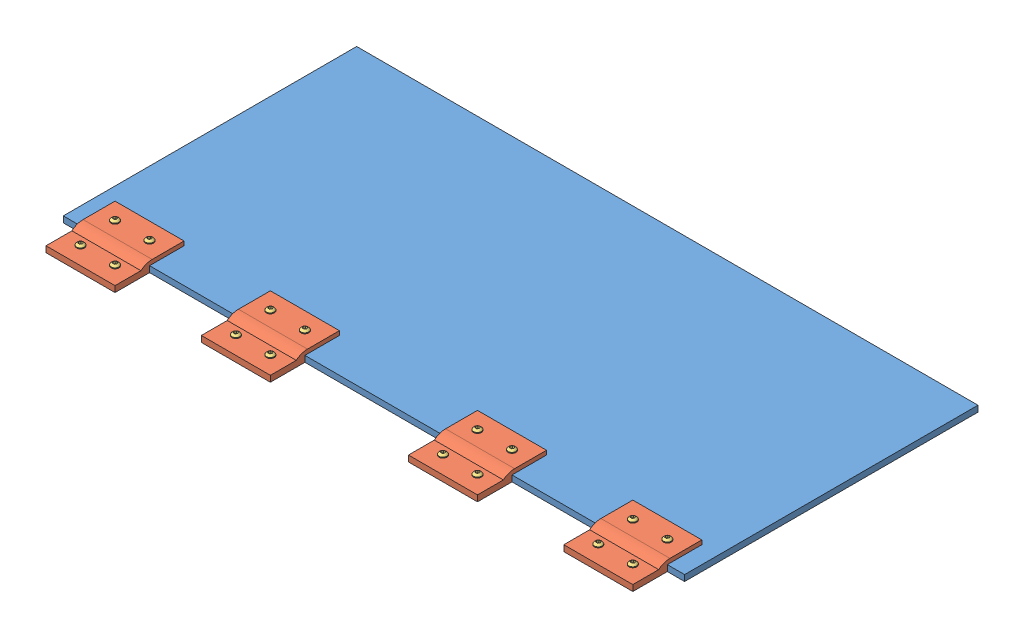
SolidWorks assembly Enclosure_left_side, configuration Default. Lengths in mm.
Overall size (360 12.64 195).
37 component instances, 5 part files, 0 mates.
Components (placement in the parent):
- Left_plexiglass_panel-1: Left_plexiglass_panel [Default] at (-180 0 0) size (360 3.5 170)
- Enclosure_holder-1: Enclosure_holder [Default] at (-170 0 20) size (40 5.5 25)
- M3x8-1: M3x8 [Default] at (-160 5.9 -10) size (4.5 9.55 4.5)
- M3x8-2: M3x8 [Default] at (-140 5.9 -10) size (4.5 9.55 4.5)
- M3x8-3: M3x8 [Default] at (-140 3.5 10) size (4.5 9.55 4.5)
- M3x8-4: M3x8 [Default] at (-160 3.5 10) size (4.5 9.55 4.5)
- M3_nut-1: M3_nut [Default] at (-160 0 -10) x (1 0 0) z (0 0 -1) size (5.5 2.58 6.35)
- M3_nut-2: M3_nut [Default] at (-140 0 -10) x (1 0 0) z (0 0 -1) size (5.5 2.58 6.35)
- M3_t_nut-1: M3_t_nut [Default] at (-160 -5 10) x (0 0 -1) z (1 0 0) size (10 5.19 6)
- M3_t_nut-3: M3_t_nut [Default] at (-140 -5 10) x (0 0 -1) z (1 0 0) size (10 5.19 6)
- M3_t_nut-4: M3_t_nut [Default] at (-50 -5 10) x (0 0 -1) z (1 0 0) size (10 5.19 6)
- M3_t_nut-5: M3_t_nut [Default] at (-70 -5 10) x (0 0 -1) z (1 0 0) size (10 5.19 6)
- M3_nut-3: M3_nut [Default] at (-50 0 -10) x (1 0 0) z (0 0 -1) size (5.5 2.58 6.35)
- M3_nut-4: M3_nut [Default] at (-70 0 -10) x (1 0 0) z (0 0 -1) size (5.5 2.58 6.35)
- M3x8-5: M3x8 [Default] at (-70 3.5 10) size (4.5 9.55 4.5)
- M3x8-6: M3x8 [Default] at (-50 3.5 10) size (4.5 9.55 4.5)
- M3x8-7: M3x8 [Default] at (-50 5.9 -10) size (4.5 9.55 4.5)
- M3x8-8: M3x8 [Default] at (-70 5.9 -10) size (4.5 9.55 4.5)
- Enclosure_holder-2: Enclosure_holder [Default] at (-80 0 20) size (40 5.5 25)
- Enclosure_holder-3: Enclosure_holder [Default] at (40 0 20) size (40 5.5 25)
- M3x8-9: M3x8 [Default] at (50 5.9 -10) x (-1 0 0) z (0 0 -1) size (4.5 9.55 4.5)
- M3_t_nut-6: M3_t_nut [Default] at (50 -0.1867 10) x (0 0 -1) z (-1 0 0) size (10 5.19 6)
- M3_nut-5: M3_nut [Default] at (50 0 -10) x (-1 0 0) z (0 0 1) size (5.5 2.58 6.35)
- M3x8-10: M3x8 [Default] at (70 3.5 10) x (-1 0 0) z (0 0 -1) size (4.5 9.55 4.5)
- M3x8-11: M3x8 [Default] at (50 3.5 10) x (-1 0 0) z (0 0 -1) size (4.5 9.55 4.5)
- M3_nut-6: M3_nut [Default] at (70 0 -10) x (-1 0 0) z (0 0 1) size (5.5 2.58 6.35)
- M3x8-12: M3x8 [Default] at (70 5.9 -10) x (-1 0 0) z (0 0 -1) size (4.5 9.55 4.5)
- M3_t_nut-7: M3_t_nut [Default] at (70 -0.1867 10) x (0 0 -1) z (-1 0 0) size (10 5.19 6)
- M3_nut-7: M3_nut [Default] at (160 0 -10) x (-1 0 0) z (0 0 1) size (5.5 2.58 6.35)
- M3_nut-8: M3_nut [Default] at (140 0 -10) x (-1 0 0) z (0 0 1) size (5.5 2.58 6.35)
- M3_t_nut-8: M3_t_nut [Default] at (140 -0.1867 10) x (0 0 -1) z (-1 0 0) size (10 5.19 6)
- M3x8-13: M3x8 [Default] at (140 5.9 -10) x (-1 0 0) z (0 0 -1) size (4.5 9.55 4.5)
- M3x8-14: M3x8 [Default] at (160 3.5 10) x (-1 0 0) z (0 0 -1) size (4.5 9.55 4.5)
- Enclosure_holder-4: Enclosure_holder [Default] at (130 0 20) size (40 5.5 25)
- M3x8-15: M3x8 [Default] at (160 5.9 -10) x (-1 0 0) z (0 0 -1) size (4.5 9.55 4.5)
- M3_t_nut-9: M3_t_nut [Default] at (160 -0.1867 10) x (0 0 -1) z (-1 0 0) size (10 5.19 6)
- M3x8-16: M3x8 [Default] at (140 3.5 10) x (-1 0 0) z (0 0 -1) size (4.5 9.55 4.5)
